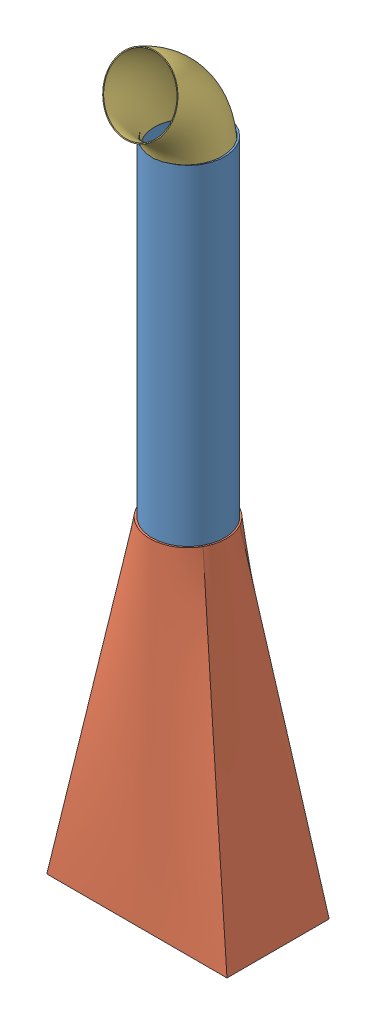
SolidWorks assembly vaccumtubeassem, configuration Default. Lengths in mm.
Overall size (104.06 433.61 76.06).
3 component instances, 3 part files, 2 mates.
Components (placement in the parent):
- vaccum tube-1: vaccum tube [Default] at (153.0936 128.5064 153.5518) x (-0.599926 0 -0.800055) z (0.800055 0 -0.599926) size (42 194 42)
- vaccum tube1-1: vaccum tube1 [Default] at (152.8704 -58.1243 153.5036) size (104.06 190.02 59.03)
- vaccum turning tube-2: vaccum turning tube [Default] at (153.0936 356.6854 181.2662) x (0 -0.383139 -0.923691) z (1 0 0) size (60.12 53.57 40)
Mates (geometry in assembly coordinates):
- Lock1: lock: unknown of vaccum tube-1; unknown of vaccum tube1-1
- Concentric2: concentric: circle of vaccum tube-1; circle of vaccum turning tube-2
